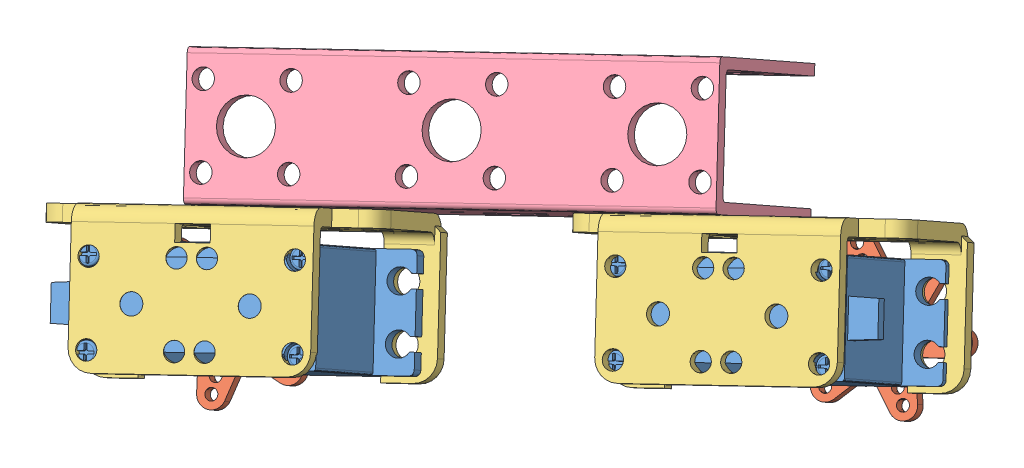
SolidWorks assembly abdomen_servo, configuration Predeterminado. Lengths in mm.
Overall size (151.57 96.7 114.19).
8 component instances, 4 part files, 8 mates.
Components (placement in the parent):
- mg946R-1: mg946R [Predeterminado] at (-344.0378 -351.8202 -241.0486) x (0.40028 -0.805595 0.436798) z (0.871511 0.187309 -0.453192) size (20.1 44.9 54.4)
- mg946R-2: mg946R [Predeterminado] at (-420.6858 -367.2889 -199.3379) x (-0.40028 0.805595 -0.436798) z (-0.871511 -0.187309 0.453192) size (20.1 44.9 54.4)
- start_horn-1: start_horn [Predeterminado] at (-348.5755 -376.5521 -282.5039) x (0.702248 0.430248 -0.567216) z (0.653149 -0.706367 0.272841) size (28.38 5.5 32)
- start_horn-2: start_horn [Predeterminado] at (-443.0023 -395.8419 -231.548) x (-0.290817 -0.721755 0.628089) z (-0.913883 0.403903 0.040992) size (28.38 5.5 32)
- abdomen_support-1: abdomen_support [Predeterminado] at (-1.2511 -2.4825 -3.432) size (151.57 87.66 109.24)
  - multi_purpose_bracket-1: multi_purpose_bracket [Predeterminado] at (-430.1174 -360.3056 -214.1479) x (0.871511 0.187309 -0.453192) z (-0.283273 -0.562078 -0.777061) size (60 27 38.5)
  - multi_purpose_bracket-2: multi_purpose_bracket [Predeterminado] at (-352.5529 -343.635 -254.482) x (0.871511 0.187309 -0.453192) z (-0.283273 -0.562078 -0.777061) size (60 27 38.5)
  - channel_bracket-1: channel_bracket [Predeterminado] at (-391.2794 -331.8617 -225.8966) x (0.871511 0.187309 -0.453192) z (-0.40028 0.805595 -0.436798) size (90 43 25)
Mates (geometry in assembly coordinates):
- Concéntrica1: concentric anti-aligned: cylinder of mg946R-1 through (-347.8673 -375.1469 -280.5612) axis (0.283273 0.562078 0.777061) radius 3; circle of start_horn-1
- Coincidente4: coincident anti-aligned: plane of mg946R-1 through (-347.8673 -375.1469 -280.5612) normal (-0.283273 -0.562078 -0.777061); plane of start_horn-1 through (-339.0498 -384.6829 -276.8779) normal (0.283273 0.562078 0.777061)
- Concéntrica4: concentric anti-aligned: cylinder of mg946R-2 through (-442.2942 -394.4367 -229.6054) axis (0.283273 0.562078 0.777061) radius 3; cylinder of start_horn-2 through (-441.4443 -392.7505 -227.2742) axis (-0.283273 -0.562078 -0.777061) radius 3.4
- Coincidente7: coincident anti-aligned: plane of mg946R-2 through (-442.2942 -394.4367 -229.6054) normal (-0.283273 -0.562078 -0.777061); plane of start_horn-2 through (-454.6316 -388.9841 -229.052) normal (0.283273 0.562078 0.777061)
- Concéntrica5: concentric aligned: cylinder of mg946R-1 through (-347.8673 -375.1469 -280.5612) axis (0.283273 0.562078 0.777061) radius 3; cylinder of abdomen_support-1/multi_purpose_bracket-2 through (-345.4645 -370.3791 -273.9699) axis (0.283273 0.562078 0.777061) radius 1.95
- Concéntrica6: concentric aligned: cylinder of mg946R-2 through (-442.2942 -394.4367 -229.6054) axis (0.283273 0.562078 0.777061) radius 3; cylinder of abdomen_support-1/multi_purpose_bracket-1 through (-440.4592 -390.7959 -224.5719) axis (0.283273 0.562078 0.777061) radius 1.95
- Paralelo1: parallel anti-aligned: plane of mg946R-2 through (-415.1338 -371.4189 -235.0511) normal (-0.40028 0.805595 -0.436798); plane of abdomen_support-1/multi_purpose_bracket-1 through (-430.1677 -365.2048 -216.2694) normal (0.40028 -0.805595 0.436798)
- Paralelo2: parallel anti-aligned: plane of mg946R-1 through (-373.782 -363.5362 -258.4075) normal (-0.40028 0.805595 -0.436798); plane of abdomen_support-1/multi_purpose_bracket-2 through (-352.6032 -348.5343 -256.6036) normal (0.40028 -0.805595 0.436798)
